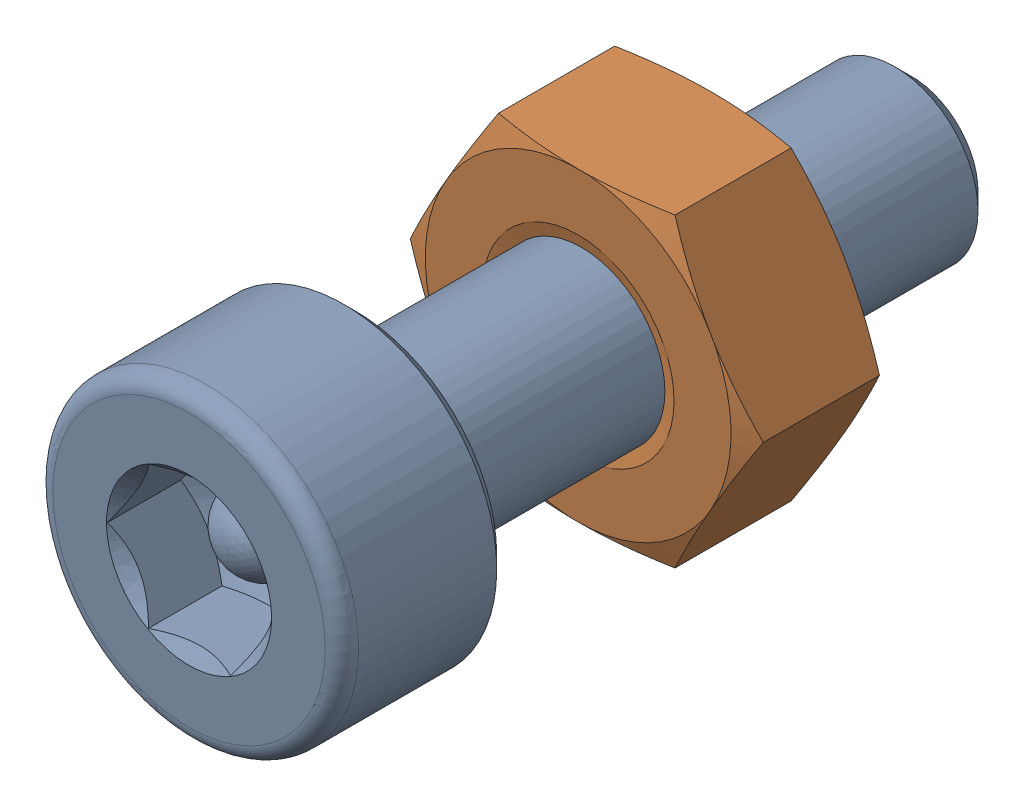
SolidWorks assembly Screw and Nut M3x010_021, configuration Varsayılan. Lengths in mm.
Overall size (6.35 5.5 13.14).
2 component instances, 2 part files, 0 mates.
Components (placement in the parent):
- M3x10-Screw020-1: M3x10-Screw020 [Varsayılan] at origin size (5.5 5.5 13.14)
- M3-Nut052-1: M3-Nut052 [Varsayılan] at (0 0 -4) x (-1 0 0) z (0 0 -1) size (6.35 5.5 2.4)
